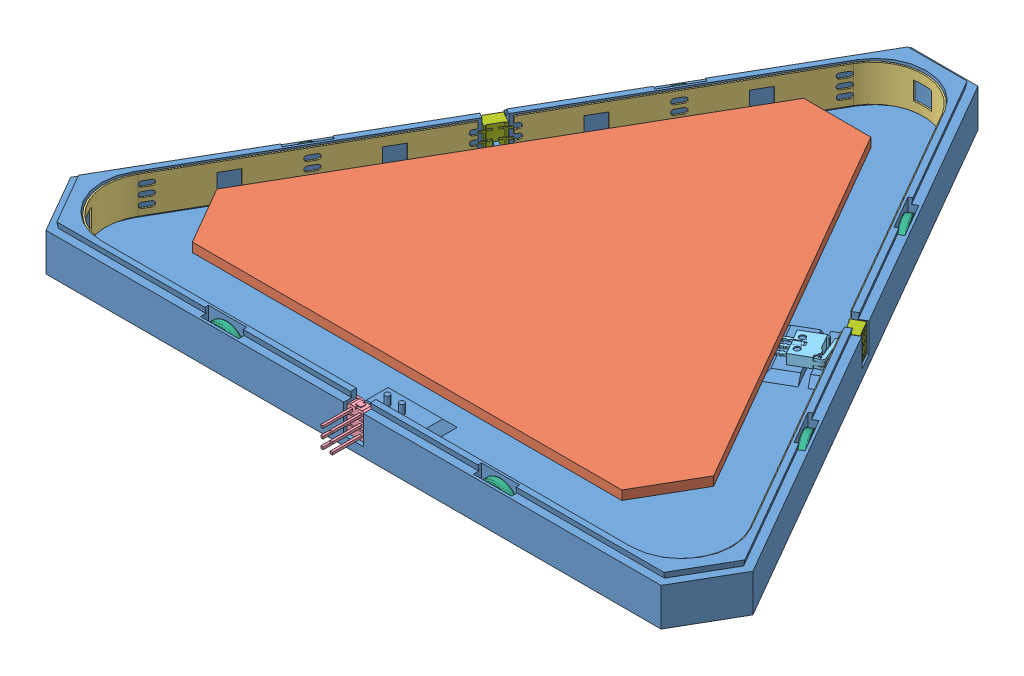
SolidWorks assembly smartleaf_triangle, configuration Défaut. Lengths in mm.
Overall size (187.52 14.05 190.18).
16 component instances, 7 part files, 48 mates.
Components (placement in the parent):
- smartleaf_triangle_bottom-1: smartleaf_triangle_bottom [Défaut] at origin size (187.52 12 162.4)
- smartleaf_triangle_top-1: smartleaf_triangle_top [Défaut] at (0 13 0) x (1 0 0) z (0 0 -1) size (136.52 2.5 118.23)
- Strip_led_ws2812_30leds-m-1: Strip_led_ws2812_30leds-m [Défaut] at (-125.2022 6.5 104.9223) x (0.5 0 -0.866025) z (0.866025 0 0.5) size (82.78 10 80.82)
- Strip_led_ws2812_30leds-m-2: Strip_led_ws2812_30leds-m [Défaut] at (153.4665 6.5 55.9671) x (-1 0 0) z (0 0 -1) size (82.78 10 80.82)
- Strip_led_ws2812_30leds-m-3: Strip_led_ws2812_30leds-m [Défaut] at (-28.2643 6.5 -160.8894) x (0.5 0 0.866025) z (-0.866025 0 0.5) size (82.78 10 80.82)
- TSM_103_02_T_DV-1: TSM_103_02_T_DV [Défaut] at (0 6.5 57.4721) x (0 -1 0) z (-1 0 0) size (7.62 11.94 7.44)
- TS0101F020P-1: TS0101F020P [Défaut] at (42.2907 4.35 -22.6845) x (-0.5 0 -0.866025) z (0.866025 0 -0.5) size (8.31 2.7 12.18)
- TS0101F020P-5: TS0101F020P [Défaut] at (-40.7907 4.35 -25.2826) x (-0.5 0 0.866025) z (-0.866025 0 -0.5) size (8.31 2.7 12.18)
- Aimant_10x2mm-1: Aimant_10x2mm [Défaut] at (37.5 6 56.4671) x (0.78482 -0.619723 0) z (0 0 1) size (10 10 2)
- Aimant_10x2mm-2: Aimant_10x2mm [Défaut] at (-37.5 6 56.6671) x (0.873152 -0.487449 0) z (0 0 1) size (10 10 2)
- Aimant_10x2mm-4: Aimant_10x2mm [Défaut] at (-67.8251 6 4.1424) x (-0.272453 -0.838497 0.471903) z (-0.866025 0 -0.5) size (10 10 2)
- Aimant_10x2mm-6: Aimant_10x2mm [Défaut] at (-30.3251 6 -60.8095) x (-0.128011 -0.966671 0.221722) z (-0.866025 0 -0.5) size (10 10 2)
- Aimant_10x2mm-8: Aimant_10x2mm [Défaut] at (30.3251 6 -60.8095) x (-0.4998 -0.028255 -0.86568) z (0.866025 0 -0.5) size (10 10 2)
- Aimant_10x2mm-10: Aimant_10x2mm [Défaut] at (67.8251 6 4.1424) x (-0.49797 -0.09001 -0.86251) z (0.866025 0 -0.5) size (10 10 2)
- 610006243021-1: 610006243021 [Défaut] at (-49.638 6.5 -28.6585) x (0 1 0) z (-0.866025 0 -0.5) size (7.62 7.21 3.7)
- 610006243021-2: 610006243021 [Défaut] at (49.638 6.5 -28.6585) x (0 1 0) z (0.866025 0 -0.5) size (7.62 7.21 3.7)
Mates (geometry in assembly coordinates):
- Coïncidente1: coincident: plane of smartleaf_triangle_bottom-1 through (0 0 0) normal (0 0 1); plane of assembly through (0 0 0) normal (0 0 1)
- Coïncidente2: coincident: plane of smartleaf_triangle_bottom-1 through (0 0 0) normal (0 1 0); plane of assembly through (0 0 0) normal (0 1 0)
- Coïncidente3: coincident: plane of smartleaf_triangle_bottom-1 through (0 0 0) normal (1 0 0); plane of assembly through (0 0 0) normal (1 0 0)
- Coïncidente5: coincident: plane of smartleaf_triangle_top-1 through (0 13 0) normal (0 0 -1); plane of assembly through (0 0 0) normal (0 0 1)
- Coïncidente6: coincident: plane of smartleaf_triangle_top-1 through (0 13 0) normal (1 0 0); plane of assembly through (0 0 0) normal (1 0 0)
- Coïncidente7: coincident: plane of smartleaf_triangle_bottom-1 through (-72.6891 1 55.9671) normal (0 0 -1); plane of Strip_led_ws2812_30leds-m-1 through (-20.2665 6.5 55.9671) normal (0 0 1)
- Coïncidente8: coincident: plane of smartleaf_triangle_bottom-1 through (-12.1244 1 -90.9342) normal (0.866025 0 0.5); plane of Strip_led_ws2812_30leds-m-1 through (-125.2022 6.5 104.9223) normal (-0.866025 0 -0.5)
- Coïncidente9: coincident: plane of smartleaf_triangle_bottom-1 through (0 6.5 0) normal (0 1 0); plane of Strip_led_ws2812_30leds-m-1 through (-125.2022 6.5 104.9223) normal (0 1 0)
- Coïncidente10: coincident: plane of smartleaf_triangle_bottom-1 through (0 6.5 0) normal (0 1 0); plane of Strip_led_ws2812_30leds-m-2 through (153.4665 6.5 55.9671) normal (0 1 0)
- Coïncidente11: coincident: plane of smartleaf_triangle_bottom-1 through (84.8135 1 34.9671) normal (-0.866025 0 0.5); plane of Strip_led_ws2812_30leds-m-2 through (58.6022 6.5 -10.4322) normal (0.866025 0 -0.5)
- Coïncidente12: coincident: plane of smartleaf_triangle_bottom-1 through (-72.6891 1 55.9671) normal (0 0 -1); plane of Strip_led_ws2812_30leds-m-2 through (153.4665 6.5 55.9671) normal (0 0 1)
- Coïncidente13: coincident: plane of smartleaf_triangle_bottom-1 through (0 6.5 0) normal (0 1 0); plane of Strip_led_ws2812_30leds-m-3 through (-28.2643 6.5 -160.8894) normal (0 1 0)
- Coïncidente14: coincident: plane of smartleaf_triangle_bottom-1 through (-12.1244 1 -90.9342) normal (0.866025 0 0.5); plane of Strip_led_ws2812_30leds-m-3 through (-38.3357 6.5 -45.5348) normal (-0.866025 0 -0.5)
- Coïncidente15: coincident: plane of smartleaf_triangle_bottom-1 through (84.8135 1 34.9671) normal (-0.866025 0 0.5); plane of Strip_led_ws2812_30leds-m-3 through (-28.2643 6.5 -160.8894) normal (0.866025 0 -0.5)
- Coïncidente17: coincident: plane of TSM_103_02_T_DV-1 through (3.7211 3.6425 55.5671) normal (0 0 1); plane of Strip_led_ws2812_30leds-m-2 through (153.4665 6.5 55.5671) normal (0 0 -1)
- Coïncidente18: coincident: plane of smartleaf_triangle_bottom-1 through (0 0 0) normal (-1 0 0); plane of TSM_103_02_T_DV-1 through (0 6.5 57.4721) normal (-1 0 0)
- Coïncidente19: coincident: plane of smartleaf_triangle_bottom-1 through (0 6.5 0) normal (0 1 0); plane of TSM_103_02_T_DV-1 through (0 6.5 57.4721) normal (0 -1 0)
- Coïncidente28: coincident: plane of smartleaf_triangle_bottom-1 through (0 3 0) normal (0 1 0); plane of TS0101F020P-1 through (47.9449 3 -20.7412) normal (0 -1 0)
- Coaxiale3: concentric: cylinder of smartleaf_triangle_bottom-1 through (40.1649 5.5 -23.7666) axis (0 -1 0) radius 0.7; cylinder of TS0101F020P-1 through (40.1649 2.865 -23.7666) axis (0 1 0) radius 0.8
- Coaxiale4: concentric: cylinder of smartleaf_triangle_bottom-1 through (42.1649 5.5 -20.3024) axis (0 -1 0) radius 0.7; cylinder of TS0101F020P-1 through (42.1649 2.865 -20.3024) axis (0 1 0) radius 0.8
- Coïncidente31: coincident: plane of smartleaf_triangle_bottom-1 through (0 12 0) normal (0 1 0); plane of smartleaf_triangle_top-1 through (0 12 0) normal (0 -1 0)
- Distance1: distance = 0.1 mm: plane of Aimant_10x2mm-1 through (37.5 6 56.4671) normal (0 0 -1); plane of smartleaf_triangle_bottom-1 through (32.25 -11.4539 56.5671) normal (0 0 1)
- Distance2: distance = 5.25 mm: cylinder of Aimant_10x2mm-1 through (37.5 6 58.4671) axis (0 0 -1) radius 5; plane of smartleaf_triangle_bottom-1 through (32.25 -11.4539 56.5671) normal (1 0 0)
- Tangent1: tangent: plane of smartleaf_triangle_bottom-1 through (0 1 -83.9342) normal (0 1 0); cylinder of Aimant_10x2mm-1 through (37.5 6 58.4671) axis (0 0 -1) radius 5
- Distance3: distance = 0.1 mm: plane of Aimant_10x2mm-2 through (-37.5 6 56.6671) normal (0 0 -1); plane of smartleaf_triangle_bottom-1 through (-32.25 -11.4539 56.5671) normal (0 0 1)
- Distance4: distance = 5.25 mm: cylinder of Aimant_10x2mm-2 through (-37.5 6 58.6671) axis (0 0 -1) radius 5; plane of smartleaf_triangle_bottom-1 through (-42.75 -11.4539 56.5671) normal (1 0 0)
- Tangent2: tangent: plane of smartleaf_triangle_bottom-1 through (0 1 -83.9342) normal (0 1 0); cylinder of Aimant_10x2mm-2 through (-37.5 6 58.6671) axis (0 0 -1) radius 5
- Distance5: distance = 0.1 mm: plane of Aimant_10x2mm-4 through (-67.8251 6 4.1424) normal (0.866025 0 0.5); plane of smartleaf_triangle_bottom-1 through (-65.1135 -11.4539 -0.3542) normal (-0.866025 0 -0.5)
- Distance6: distance = 5.25 mm: cylinder of Aimant_10x2mm-4 through (-69.5572 6 3.1424) axis (0.866025 0 0.5) radius 5; plane of smartleaf_triangle_bottom-1 through (-65.1135 -11.4539 -0.3542) normal (-0.5 0 0.866025)
- Tangent3: tangent: plane of smartleaf_triangle_bottom-1 through (0 1 -83.9342) normal (0 1 0); cylinder of Aimant_10x2mm-4 through (-69.5572 6 3.1424) axis (0.866025 0 0.5) radius 5
- Distance7: distance = 0.1 mm: plane of Aimant_10x2mm-6 through (-30.3251 6 -60.8095) normal (0.866025 0 0.5); plane of smartleaf_triangle_bottom-1 through (-32.8635 -11.4539 -56.2129) normal (-0.866025 0 -0.5)
- Distance8: distance = 5.25 mm: cylinder of Aimant_10x2mm-6 through (-32.0572 6 -61.8095) axis (0.866025 0 0.5) radius 5; plane of smartleaf_triangle_bottom-1 through (-27.6135 -11.4539 -65.3061) normal (-0.5 0 0.866025)
- Tangent4: tangent: plane of smartleaf_triangle_bottom-1 through (0 1 -83.9342) normal (0 1 0); cylinder of Aimant_10x2mm-6 through (-32.0572 6 -61.8095) axis (0.866025 0 0.5) radius 5
- Distance9: distance = 0.1 mm: plane of Aimant_10x2mm-8 through (30.3251 6 -60.8095) normal (-0.866025 0 0.5); plane of smartleaf_triangle_bottom-1 through (32.8635 -11.4539 -56.2129) normal (0.866025 0 -0.5)
- Distance10: distance = 5.25 mm: cylinder of Aimant_10x2mm-8 through (32.0572 6 -61.8095) axis (-0.866025 0 0.5) radius 5; plane of smartleaf_triangle_bottom-1 through (32.8635 -11.4539 -56.2129) normal (-0.5 0 -0.866025)
- Tangent5: tangent: plane of smartleaf_triangle_bottom-1 through (0 1 -83.9342) normal (0 1 0); cylinder of Aimant_10x2mm-8 through (32.0572 6 -61.8095) axis (-0.866025 0 0.5) radius 5
- Distance11: distance = 0.1 mm: plane of Aimant_10x2mm-10 through (67.8251 6 4.1424) normal (-0.866025 0 0.5); plane of smartleaf_triangle_bottom-1 through (65.1135 -11.4539 -0.3542) normal (0.866025 0 -0.5)
- Distance12: distance = 5.25 mm: cylinder of Aimant_10x2mm-10 through (69.5572 6 3.1424) axis (-0.866025 0 0.5) radius 5; plane of smartleaf_triangle_bottom-1 through (70.3635 -11.4539 8.739) normal (-0.5 0 -0.866025)
- Tangent6: tangent: plane of smartleaf_triangle_bottom-1 through (0 1 -83.9342) normal (0 1 0); cylinder of Aimant_10x2mm-10 through (69.5572 6 3.1424) axis (-0.866025 0 0.5) radius 5
- Coïncidente32: coincident: plane of smartleaf_triangle_bottom-1 through (0 0 0) normal (-0.5 0 0.866025); plane of 610006243021-1 through (-49.638 6.5 -28.6585) normal (0.5 0 -0.866025)
- Coïncidente33: coincident: plane of smartleaf_triangle_bottom-1 through (0 6.5 0) normal (0 1 0); plane of 610006243021-1 through (-49.638 6.5 -28.6585) normal (0 1 0)
- Coïncidente34: coincident: plane of Strip_led_ws2812_30leds-m-1 through (-124.8557 6.5 105.1223) normal (0.866025 0 0.5); plane of 610006243021-1 through (-49.0825 9.04 -26.1208) normal (-0.866025 0 -0.5)
- Coïncidente35: coincident: plane of smartleaf_triangle_bottom-1 through (0 0 0) normal (0.5 0 0.866025); plane of 610006243021-2 through (49.638 6.5 -28.6585) normal (0.5 0 0.866025)
- Coïncidente36: coincident: plane of smartleaf_triangle_bottom-1 through (0 6.5 0) normal (0 1 0); plane of 610006243021-2 through (49.638 6.5 -28.6585) normal (0 1 0)
- Coïncidente37: coincident: plane of Strip_led_ws2812_30leds-m-3 through (-28.6107 6.5 -160.6894) normal (-0.866025 0 0.5); plane of 610006243021-2 through (47.1625 9.04 -29.4463) normal (0.866025 0 -0.5)
- Coaxiale5: concentric: cylinder of smartleaf_triangle_bottom-1 through (-38.6649 5.5 -26.3646) axis (0 -1 0) radius 0.7; cylinder of TS0101F020P-5 through (-38.6649 2.865 -26.3646) axis (0 1 0) radius 0.8
- Coaxiale6: concentric: circle of smartleaf_triangle_bottom-1; cylinder of TS0101F020P-5 through (-40.6649 2.865 -22.9005) axis (0 1 0) radius 0.8
- Coïncidente38: coincident: plane of smartleaf_triangle_bottom-1 through (0 3 0) normal (0 1 0); plane of TS0101F020P-5 through (-41.9349 3 -31.1509) normal (0 -1 0)
